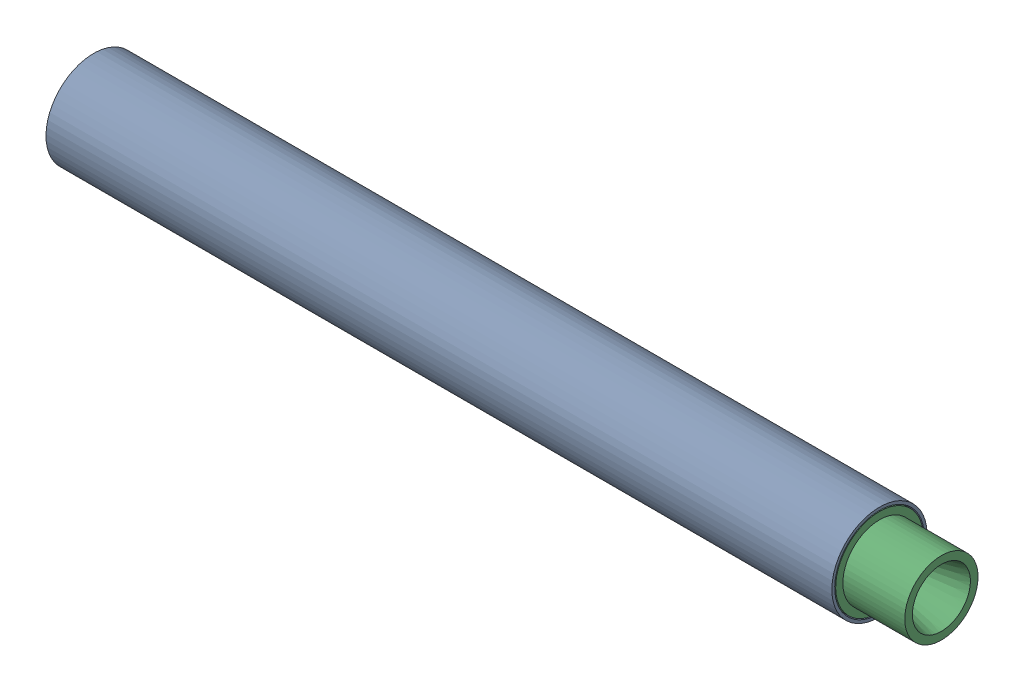
SolidWorks assembly Assem1, configuration Default. Lengths in mm.
Overall size (890 100 100).
3 component instances, 3 part files, 4 mates.
Components (placement in the parent):
- Casing-1: Casing [Default] at (-408.5639 52.4983 -37.7436) x (0 0 -1) z (0 -1 0) size (100 825 100)
- Bulkhead-1: Bulkhead [Default] at (-408.5639 52.4983 -37.7436) x (1 0 0) z (0 -0.08158 0.996667) size (50 92 92)
- Nozzle2-1: Nozzle2 [Default] at (481.4361 52.4983 -37.7436) size (115 92 92)
Mates (geometry in assembly coordinates):
- Concentric1: concentric: cylinder of Casing-1 through (416.4361 52.4983 -37.7436) axis (-1 0 0) radius 50; cylinder of Bulkhead-1 through (-408.5639 52.4983 -37.7436) axis (-1 0 0) radius 46
- Coincident2: coincident aligned: plane of Casing-1 through (-408.5639 52.4983 -37.7436) normal (-1 0 0); plane of Bulkhead-1 through (-408.5639 52.4983 -37.7436) normal (-1 0 0)
- Concentric2: concentric: cylinder of Casing-1 through (416.4361 52.4983 -37.7436) axis (-1 0 0) radius 50; cylinder of Nozzle2-1 through (481.4361 52.4983 -37.7436) axis (1 0 0) radius 46
- Coincident3: coincident aligned: plane of Casing-1 through (416.4361 52.4983 -37.7436) normal (1 0 0); plane of Nozzle2-1 through (416.4361 90.9419 -37.7436) normal (1 0 0)
